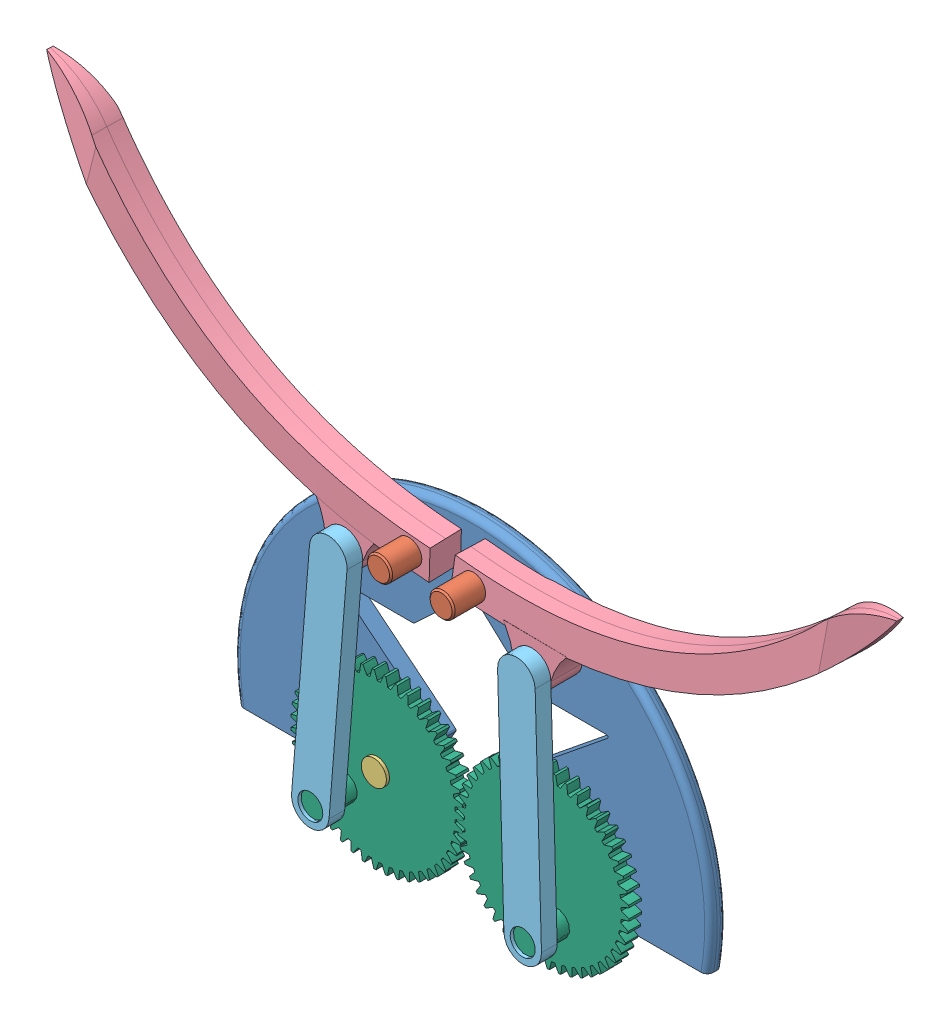
SolidWorks assembly Assem1, configuration Default. Lengths in mm.
Overall size (281.07 187.88 28).
11 component instances, 6 part files, 23 mates.
Components (placement in the parent):
- Part5-1: Part5 [Default] at (11.0823 35.0711 82.7503) size (152.39 89.62 5.23)
- Part6-1: Part6 [Default] at (21.0823 115.0711 80.7503) x (0.860098 0.510129 0) z (0.510129 -0.860098 0) size (10 27 10)
- Part8-1: Part8 [Default] at (-15.4177 43.0711 79.7503) x (0.949398 0.314076 0) z (0 0 1) size (10 10 13)
- wing-1: wing [Default] at (96.5093 105.9483 92.7503) x (0 0 1) z (-0.998261 0.058952 0) size (13.65 80.05 137.28)
- Part6-2: Part6 [Default] at (1.0823 115.0711 80.7503) x (0.947765 -0.318968 0) z (-0.318968 -0.947765 0) size (10 27 10)
- Part8-2: Part8 [Default] at (37.5823 43.0711 79.7503) x (0.7719 -0.635744 0) z (0 0 1) size (10 10 13)
- wing-2: wing [Default] at (-74.7736 119.3525 92.7503) x (0 0 -1) z (0.993074 -0.117487 0) size (13.65 80.05 137.28)
- Part10-3: Part10 [Default] at (41.116 65.815 102.7503) x (0.999606 0.02808 0) z (0 0 -1) size (12 84 15)
- Part10-4: Part10 [Default] at (-22.8438 69.4666 102.7503) x (0.996825 -0.079622 0) z (0 0 -1) size (12 84 15)
- spur gear_-1: spur gear_ [ISO - Spur gear 1.125M 47T 20PA 4FW ---S47A75H50L8.0N] at (37.5823 43.0711 87.7503) x (0 0 1) z (-0.945847 -0.324613 0) size (14 55.08 55.11)
- spur gear_-2: spur gear_ [ISO - Spur gear 1.125M 47T 20PA 4FW ---S47A75H50L8.0N] at (-15.4177 43.0711 87.7503) x (0 0 1) z (-0.677872 0.73518 0) size (14 55.08 55.11)
Mates (geometry in assembly coordinates):
- Coincident1: coincident: plane of assembly; plane of assembly; plane of Part5-1 through (11.0823 48.4994 82.7503) normal (0 0 -1); plane of Part6-1 through (21.0823 115.0711 82.7503) normal (0 0 1)
- Concentric1: concentric: cylinder of assembly; cylinder of assembly; cylinder of Part5-1 through (21.0823 115.0711 82.7503) axis (0 0 1) radius 4; cylinder of Part6-1 through (21.0823 115.0711 107.7503) axis (0 0 -1) radius 4
- Coincident2: coincident: plane of assembly; plane of assembly; plane of Part5-1 through (11.0823 48.4994 82.7503) normal (0 0 -1); plane of Part6-2 through (1.0823 115.0711 82.7503) normal (0 0 1)
- Concentric2: concentric: cylinder of assembly; cylinder of assembly; cylinder of Part5-1 through (1.0823 115.0711 82.7503) axis (0 0 1) radius 4; cylinder of Part6-2 through (1.0823 115.0711 107.7503) axis (0 0 -1) radius 4
- Concentric4: concentric: cylinder of assembly; cylinder of assembly; cylinder of Part5-1 through (-15.4177 43.0711 82.7503) axis (0 0 1) radius 4; cylinder of Part8-1 through (-15.4177 43.0711 92.7503) axis (0 0 -1) radius 4
- Coincident3: coincident: plane of assembly; plane of assembly; plane of Part5-1 through (11.0823 48.4994 82.7503) normal (0 0 -1); plane of Part8-1 through (-15.4177 43.0711 82.7503) normal (0 0 1)
- Concentric5: concentric: cylinder of assembly; cylinder of assembly; cylinder of Part5-1 through (37.5823 43.0711 82.7503) axis (0 0 1) radius 4; cylinder of Part8-2 through (37.5823 43.0711 92.7503) axis (0 0 -1) radius 4
- Coincident4: coincident: plane of assembly; plane of assembly; plane of Part5-1 through (11.0823 48.4994 82.7503) normal (0 0 -1); plane of Part8-2 through (37.5823 43.0711 82.7503) normal (0 0 1)
- Concentric14: concentric: cylinder of assembly; cylinder of assembly; cylinder of Part6-1 through (21.0823 115.0711 107.7503) axis (0 0 -1) radius 4; cylinder of wing-1 through (21.0823 115.0711 72.7503) axis (0 0 1) radius 4
- Concentric15: concentric: cylinder of assembly; cylinder of assembly; cylinder of Part6-2 through (1.0823 115.0711 107.7503) axis (0 0 -1) radius 4; cylinder of wing-2 through (1.0823 115.0711 112.7503) axis (0 0 -1) radius 4
- Coincident14: coincident: plane of assembly; point of assembly; plane of Part5-1 through (11.0823 48.4994 87.7503) normal (0 0 1); point of wing-2
- Coincident15: coincident: plane of assembly; point of assembly; plane of Part5-1 through (11.0823 48.4994 87.7503) normal (0 0 1); point of wing-1
- Concentric27: concentric: cylinder of assembly; cylinder of assembly; cylinder of wing-1 through (40.1051 101.8008 87.7503) axis (0 0 1) radius 4; cylinder of Part10-3 through (40.1051 101.8008 87.7503) axis (0 0 1) radius 4
- Coincident22: coincident: plane of assembly; plane of assembly; plane of wing-1 through (40.4586 101.806 97.7503) normal (0 0 1); plane of Part10-3 through (40.1051 101.8008 97.7503) normal (0 0 -1)
- Coincident23: coincident: plane of assembly; plane of assembly; plane of wing-2 through (-20.3244 105.4196 97.7503) normal (0 0 1); plane of Part10-4 through (-19.9774 105.3523 97.7503) normal (0 0 -1)
- Concentric28: concentric: cylinder of assembly; cylinder of assembly; cylinder of wing-2 through (-19.9774 105.3523 97.7503) axis (0 0 -1) radius 4; cylinder of Part10-4 through (-19.9774 105.3523 87.7503) axis (0 0 1) radius 4
- Concentric29: concentric: cylinder of assembly; cylinder of assembly; cylinder of Part8-2 through (37.5823 43.0711 92.7503) axis (0 0 -1) radius 4; cylinder of spur gear_-1 through (37.5823 43.0711 137.7504) axis (0 0 -1) radius 4
- Concentric30: concentric: cylinder of assembly; cylinder of assembly; cylinder of Part10-3 through (42.1269 29.8292 97.7503) axis (0 0 1) radius 4; cylinder of spur gear_-1 through (42.1269 29.8292 101.7503) axis (0 0 -1) radius 4
- Coincident24: coincident: plane of assembly; plane of assembly; plane of Part5-1 through (11.0823 48.4994 87.7503) normal (0 0 1); plane of spur gear_-1 through (37.5823 43.0711 87.7503) normal (0 0 -1)
- Concentric32: concentric: cylinder of assembly; cylinder of assembly; cylinder of Part8-1 through (-15.4177 43.0711 92.7503) axis (0 0 -1) radius 4; cylinder of spur gear_-2 through (-15.4177 43.0711 137.7504) axis (0 0 -1) radius 4
- Coincident25: coincident: plane of assembly; plane of assembly; plane of Part5-1 through (11.0823 48.4994 87.7503) normal (0 0 1); plane of spur gear_-2 through (-15.4177 43.0711 87.7503) normal (0 0 -1)
- Concentric33: concentric: cylinder of assembly; cylinder of assembly; cylinder of Part10-4 through (-25.7102 33.5809 97.7503) axis (0 0 1) radius 4; cylinder of spur gear_-2 through (-25.7102 33.5809 101.7503) axis (0 0 -1) radius 4
- GearMate3: gear = 0.5 : 1 mm: cylinder of assembly; cylinder of assembly; cylinder of spur gear_-1 through (14.2484 51.5979 91.7503) axis (0 0 -1) radius 10.575; cylinder of spur gear_-2 through (7.7392 34.0743 91.7503) axis (0 0 -1) radius 10.575
